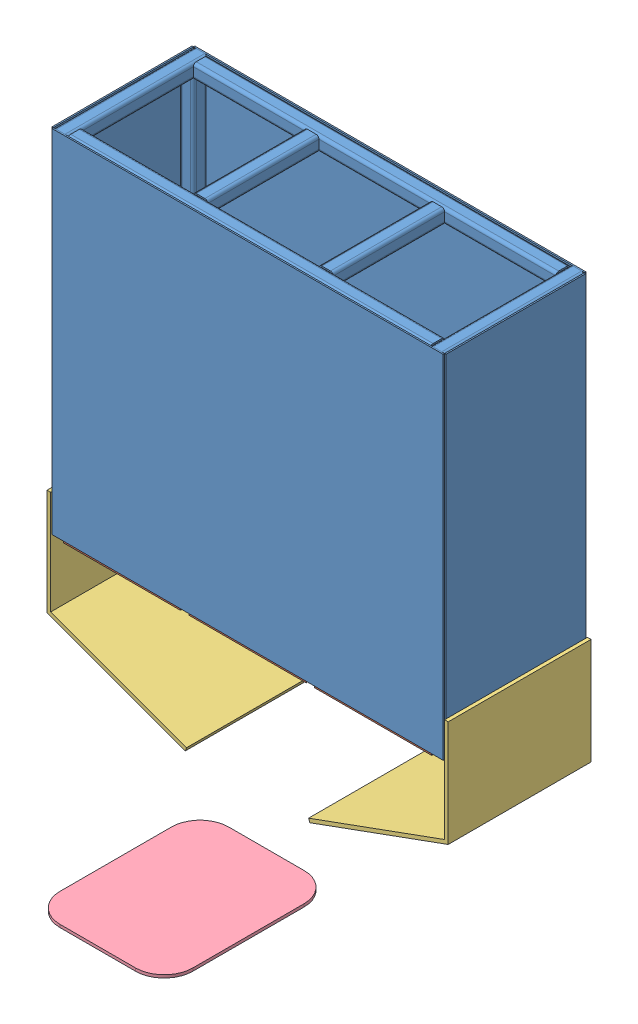
SolidWorks assembly Package_Dropoff_V1, configuration Default. Lengths in mm.
Overall size (559 794.8 362.97).
12 component instances, 4 part files, 35 mates.
Components (placement in the parent):
- Package_Dropoff_Frame_V1-1: Package_Dropoff_Frame_V1 [Default<As Machined>] at origin size (549 490 199)
- Package_Dropoff_Bottom_Door_V1-2: Package_Dropoff_Bottom_Door_V1 [Default] at (0 -20 -104.5) x (-1 0 0) z (0 -1 0) size (163 94.5 2)
- Package_Dropoff_Bottom_Door_V1-3: Package_Dropoff_Bottom_Door_V1 [Default] at (155 -22 0) x (1 0 0) z (0 1 0) size (163 94.5 2)
- Package_Dropoff_Bottom_Door_V1-4: Package_Dropoff_Bottom_Door_V1 [Default] at (330 -22 0) x (1 0 0) z (0 1 0) size (163 94.5 2)
- Package_Dropoff_Bottom_Door_V1-5: Package_Dropoff_Bottom_Door_V1 [Default] at (330 -22 -104.5) x (1 0 0) z (0 1 0) size (163 94.5 2)
- Package_Dropoff_Bottom_Door_V1-6: Package_Dropoff_Bottom_Door_V1 [Default] at (505 -22 0) x (1 0 0) z (0 1 0) size (163 94.5 2)
- Package_Dropoff_Bottom_Door_V1-7: Package_Dropoff_Bottom_Door_V1 [Default] at (505 -22 -104.5) x (1 0 0) z (0 1 0) size (163 94.5 2)
- Package_Slide_Gaurd-1: Package_Slide_Gaurd [Default] at origin size (194.5 218.17 199)
- Package_Slide_Gaurd-2: Package_Slide_Gaurd [Default] at (505 0 -155) x (-1 0 0) z (0 0 -1) size (194.5 218.17 199)
- Package_Dropoff_Bottom_Door_V1-1: Package_Dropoff_Bottom_Door_V1 [Default] at (0 -20 0) x (-1 0 0) z (0 -1 0) size (163 94.5 2) (hidden)
- Package_Dropoff_Bottom_Door_V1-8: Package_Dropoff_Bottom_Door_V1 [Default] at (0 -42 22) x (-1 0 0) z (0 0 1) size (163 94.5 2) (hidden)
- Vehicle_Base-1: Vehicle_Base [Default] at (207.7877 -324.7993 68.4748) size (185 4 235)
Mates (geometry in assembly coordinates):
- Coincident1: coincident aligned: plane of Package_Dropoff_Frame_V1-1 through (0 0 0) normal (0 0 1)
- Coincident2: coincident aligned: plane of Package_Dropoff_Frame_V1-1 through (0 0 0) normal (0 1 0)
- Coincident3: coincident aligned: plane of Package_Dropoff_Frame_V1-1 through (0 0 0) normal (1 0 0)
- InPlace1: in place: plane of ? through (-20 -20 22) normal (0 -1 0); plane of Package_Dropoff_Bottom_Door_V1-1 through (0 -20 0) normal (0 -1 0); moOrthogonalPlaneRef_w of ? through (-20 -20 22) normal (0 -1 0); plane of Package_Dropoff_Bottom_Door_V1-1 through (0 -20 0) normal (0 0 -1); plane of ? through (-20 -20 22) normal (0 -1 0); plane of Package_Dropoff_Bottom_Door_V1-1 through (0 -20 0) normal (-1 0 0); plane of ? through (-20 -20 22) normal (0 -1 0); unknown of Package_Dropoff_Bottom_Door_V1-1
- Coincident4: coincident aligned: plane of Package_Dropoff_Frame_V1-1; plane of Package_Dropoff_Bottom_Door_V1-1
- Coincident5: coincident aligned: moOrthogonalPlaneRef_w of Package_Dropoff_Frame_V1-1 through (0 -20 0) normal (0 0 -1); plane of Package_Dropoff_Bottom_Door_V1-1 through (0 -20 0) normal (0 0 -1)
- Coincident6: coincident anti-aligned: moOrthogonalPlaneRef_w of Package_Dropoff_Frame_V1-1 through (0 -20 0) normal (1 0 0); plane of Package_Dropoff_Bottom_Door_V1-1 through (0 -20 0) normal (-1 0 0)
- Coincident7: coincident aligned: line of Package_Dropoff_Frame_V1-1 through (-20 -20 -177) axis (1 0 0); line of Package_Dropoff_Bottom_Door_V1-2 through (-4 -20 -177) axis (1 0 0)
- Coincident8: coincident aligned: plane of Package_Dropoff_Bottom_Door_V1-1 through (-4 -22 0) normal (-1 0 0); plane of Package_Dropoff_Bottom_Door_V1-2 through (-4 -22 -104.5) normal (-1 0 0)
- LimitAngle1: limit planar angle = 0 rad anti-aligned: plane of Package_Dropoff_Frame_V1-1 through (-4 -20 -155) normal (0 -1 0); plane of Package_Dropoff_Bottom_Door_V1-2 through (0 -20 -104.5) normal (0 1 0)
- Coincident11: coincident anti-aligned: line of Package_Dropoff_Frame_V1-1 through (-20 -20 22) axis (1 0 0); line of Package_Dropoff_Bottom_Door_V1-3 through (159 -20 22) axis (-1 0 0)
- Coincident12: coincident aligned: plane of Package_Dropoff_Bottom_Door_V1-1 through (-4 -22 0) normal (-1 0 0); plane of Package_Dropoff_Bottom_Door_V1-3 through (-4 -20 0) normal (-1 0 0)
- LimitAngle2: limit planar angle = 0 rad anti-aligned: plane of Package_Dropoff_Frame_V1-1 through (-4 -20 -155) normal (0 -1 0); plane of Package_Dropoff_Bottom_Door_V1-3 through (155 -20 0) normal (0 1 0)
- Coincident13: coincident anti-aligned: line of Package_Dropoff_Frame_V1-1 through (-20 -20 22) axis (1 0 0); line of Package_Dropoff_Bottom_Door_V1-4 through (334 -20 22) axis (-1 0 0)
- Coincident14: coincident: line of Package_Dropoff_Frame_V1-1 through (171 -20 -155) axis (0 0 1); plane of Package_Dropoff_Bottom_Door_V1-4 through (171 -20 0) normal (-1 0 0)
- LimitAngle3: limit planar angle = 0 rad anti-aligned: plane of Package_Dropoff_Bottom_Door_V1-4 through (330 -20 0) normal (0 1 0); plane of Package_Dropoff_Frame_V1-1 through (171 -20 -155) normal (0 -1 0)
- Coincident15: coincident anti-aligned: line of Package_Dropoff_Frame_V1-1 through (-20 -20 -177) axis (1 0 0); line of Package_Dropoff_Bottom_Door_V1-5 through (334 -20 -177) axis (-1 0 0)
- Coincident16: coincident aligned: plane of Package_Dropoff_Bottom_Door_V1-4 through (171 -20 0) normal (-1 0 0); plane of Package_Dropoff_Bottom_Door_V1-5 through (171 -20 -104.5) normal (-1 0 0)
- LimitAngle4: limit planar angle = 0 rad anti-aligned: plane of Package_Dropoff_Bottom_Door_V1-5 through (330 -20 -104.5) normal (0 1 0); plane of Package_Dropoff_Frame_V1-1 through (346 -20 -155) normal (0 -1 0)
- Coincident17: coincident anti-aligned: line of Package_Dropoff_Frame_V1-1 through (-20 -20 22) axis (1 0 0); line of Package_Dropoff_Bottom_Door_V1-6 through (509 -20 22) axis (-1 0 0)
- Coincident18: coincident: line of Package_Dropoff_Frame_V1-1 through (346 -20 -155) axis (0 0 1); plane of Package_Dropoff_Bottom_Door_V1-6 through (346 -20 0) normal (-1 0 0)
- LimitAngle5: limit planar angle = 0 rad anti-aligned: plane of Package_Dropoff_Bottom_Door_V1-6 through (505 -20 0) normal (0 1 0); plane of Package_Dropoff_Frame_V1-1 through (346 -20 -155) normal (0 -1 0)
- Coincident19: coincident anti-aligned: line of Package_Dropoff_Frame_V1-1 through (-20 -20 -177) axis (1 0 0); line of Package_Dropoff_Bottom_Door_V1-7 through (509 -20 -177) axis (-1 0 0)
- Coincident20: coincident aligned: plane of Package_Dropoff_Bottom_Door_V1-6 through (346 -20 0) normal (-1 0 0); plane of Package_Dropoff_Bottom_Door_V1-7 through (346 -20 -104.5) normal (-1 0 0)
- LimitAngle6: limit planar angle = 0 rad anti-aligned: plane of Package_Dropoff_Frame_V1-1 through (509 -20 0) normal (0 -1 0); plane of Package_Dropoff_Bottom_Door_V1-7 through (505 -20 -104.5) normal (0 1 0)
- Coincident21: coincident aligned: plane of Package_Dropoff_Bottom_Door_V1-1 through (-4 -22 0) normal (-1 0 0); plane of Package_Dropoff_Bottom_Door_V1-8 through (-4 -42 24) normal (-1 0 0)
- Coincident22: coincident aligned: line of Package_Dropoff_Bottom_Door_V1-1 through (-4 -20 22) axis (1 0 0); line of Package_Dropoff_Bottom_Door_V1-8 through (-4 -20 22) axis (1 0 0)
- Perpendicular1: perpendicular: plane of Package_Dropoff_Bottom_Door_V1-1 through (0 -22 0) normal (0 -1 0); plane of Package_Dropoff_Bottom_Door_V1-8 through (0 -42 22) normal (0 0 -1)
- InPlace2: in place: plane of ? through (0 0 0) normal (0 0 1); plane of ? through (0 0 0) normal (0 1 0); plane of ? through (0 0 0) normal (1 0 0); unknown of ?
- Coincident23: coincident aligned: 
- Coincident24: coincident aligned: plane of Package_Slide_Gaurd-1 through (0 0 0) normal (0 1 0)
- Coincident25: coincident anti-aligned: plane of Package_Slide_Gaurd-1 through (0 0 0) normal (1 0 0)
- Coincident26: coincident anti-aligned: plane of Package_Dropoff_Frame_V1-1 through (527 0 0) normal (1 0 0); plane of Package_Slide_Gaurd-2 through (527 0 314.282) normal (-1 0 0)
- Coincident27: coincident aligned: plane of Package_Slide_Gaurd-1 through (0 0 22) normal (0 0 1); plane of Package_Slide_Gaurd-2 through (505 0 22) normal (0 0 1)
- Coincident28: coincident aligned: plane of Package_Slide_Gaurd-1 through (0 30 -469.282) normal (0 1 0); plane of Package_Slide_Gaurd-2 through (505 30 314.282) normal (0 1 0)
